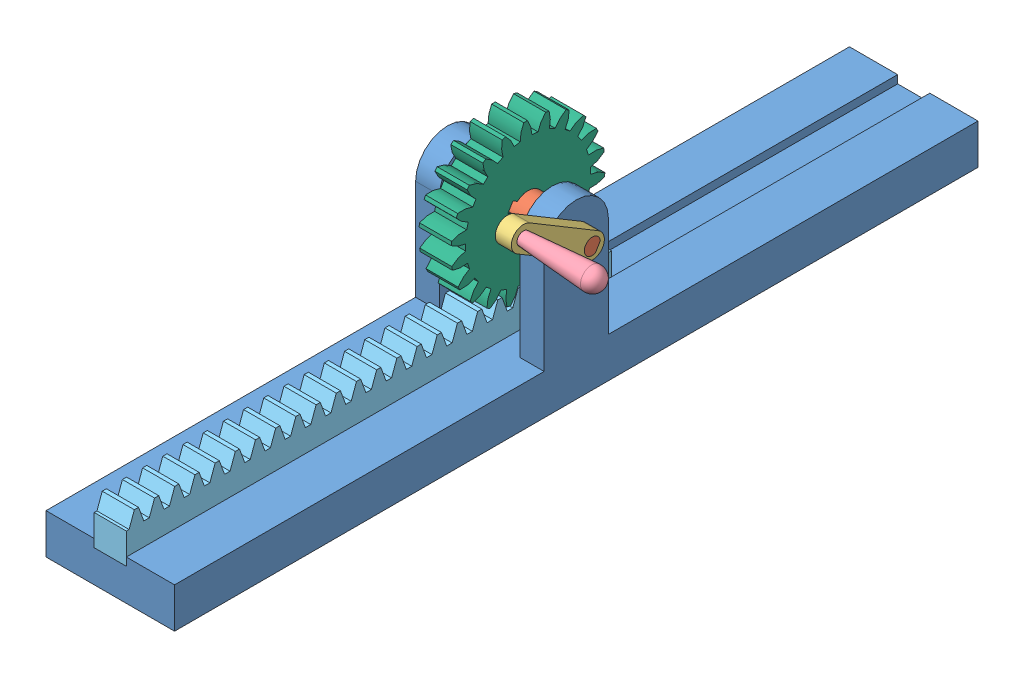
SolidWorks assembly montaj, configuration Varsayılan. Lengths in mm.
Overall size (140 153.16 500).
6 component instances, 6 part files, 16 mates.
Components (placement in the parent):
- Gövde-1: Gövde [Varsayılan] at (-10.9538 -55.8223 500) size (80 107.5 500)
- Mil-2: Mil [Varsayılan] at (-50.9538 31.6777 500) x (1 0 0) z (0 0.858106 -0.513472) size (90 20 20)
- Çevirme kolu-3: Çevirme kolu [Varsayılan] at (29.0462 57.3513 542.9053) x (0 -0.513472 -0.858106) z (1 0 0) size (65 15 10)
- Çevirme Pimi-2: Çevirme Pimi [Varsayılan] at (89.0462 57.3513 542.9053) x (-1 0 0) z (0 0.009212 -0.999958) size (60 14 14)
- kramayer-1: kramayer [kramayer] at (-0.9538 -35.8223 750) x (0 0 -1) z (1 0 0) size (302 28 20)
- silindir düz dişli-1: silindir düz dişli [silindir düz dişli] at (-20.9538 31.6777 500) x (1 0 0) z (0 -0.858106 0.513472) size (20 95.32 96)
Mates (geometry in assembly coordinates):
- Eş Merkezli7: concentric anti-aligned: cylinder of Gövde-1 through (-35.9538 31.6777 500) axis (-1 0 0) radius 7.5; cylinder of Mil-2 through (39.0462 31.6777 500) axis (1 0 0) radius 10
- Çakışık13: coincident anti-aligned: plane of Gövde-1 through (14.0462 31.6777 500) normal (-1 0 0); plane of Mil-2 through (14.0462 26.5429 491.4189) normal (1 0 0)
- Eş Merkezli10: concentric anti-aligned: cylinder of Mil-2 through (39.0462 31.6777 500) axis (1 0 0) radius 5; cylinder of Çevirme kolu-3 through (39.0462 31.6777 500) axis (-1 0 0) radius 5
- Paralel8: parallel anti-aligned: plane of Mil-2 through (29.0462 3.8806 511.9717) normal (0 -0.513472 -0.858106); plane of Çevirme kolu-3 through (39.0462 33.5697 495.3718) normal (0 0.513472 0.858106)
- Çakışık18: coincident anti-aligned: circle of Mil-2; plane of Çevirme kolu-3 through (29.0462 57.3513 542.9053) normal (-1 0 0)
- Eş Merkezli12: concentric anti-aligned: cylinder of Çevirme kolu-3 through (39.0462 57.3513 542.9053) axis (-1 0 0) radius 4; cylinder of Çevirme Pimi-2 through (89.0462 57.3513 542.9053) axis (1 0 0) radius 4
- Çakışık28: coincident aligned: plane of Çevirme kolu-3 through (39.0462 57.3513 542.9053) normal (1 0 0); circle of Çevirme Pimi-2
- Çakışık29: coincident anti-aligned: plane of Gövde-1 through (-20.9538 -35.8223 750) normal (0 1 0); plane of kramayer-1 through (-20.9538 -35.8223 750) normal (0 -1 0)
- Çakışık31: coincident anti-aligned: plane of Gövde-1 through (-0.9538 -30.8223 750) normal (-1 0 0); plane of kramayer-1 through (-0.9538 -7.8223 750) normal (1 0 0)
- Eş Merkezli13: concentric anti-aligned: cylinder of Mil-2 through (39.0462 31.6777 500) axis (1 0 0) radius 10; cylinder of silindir düz dişli-1 through (29.0463 31.6777 500) axis (-1 0 0) radius 10
- Paralel13: parallel aligned: plane of Mil-2 through (-20.9538 2.8536 510.2555) normal (0 -0.513472 -0.858106); plane of silindir düz dişli-1 through (29.0463 35.6758 512.5242) normal (0 -0.513472 -0.858106)
- Eş Merkezli14: concentric anti-aligned: cylinder of Mil-2 through (39.0462 31.6777 500) axis (1 0 0) radius 10; cylinder of silindir düz dişli-1 through (29.0463 31.6777 500) axis (-1 0 0) radius 10
- Paralel18: parallel aligned: plane of Mil-2 through (-20.9538 2.8536 510.2555) normal (0 -0.513472 -0.858106); plane of silindir düz dişli-1 through (29.0463 35.6758 512.5242) normal (0 -0.513472 -0.858106)
- Çakışık40: coincident anti-aligned: plane of Mil-2 through (-20.9538 -1.7453 502.5699) normal (1 0 0); plane of silindir düz dişli-1 through (-20.9538 31.6777 500) normal (-1 0 0)
- RackPinionMate1: rack pinion = 88 mm: line of kramayer-1 through (-0.9538 -16.8223 626.039) axis (0 0 -1); circle of silindir düz dişli-1
- Uzaklığı Sınırla2: limit distance = 0 mm aligned: plane of kramayer-1 through (-20.9538 -35.8223 750) normal (0 0 1); plane of Gövde-1 through (-10.9538 -55.8223 750) normal (0 0 1)
